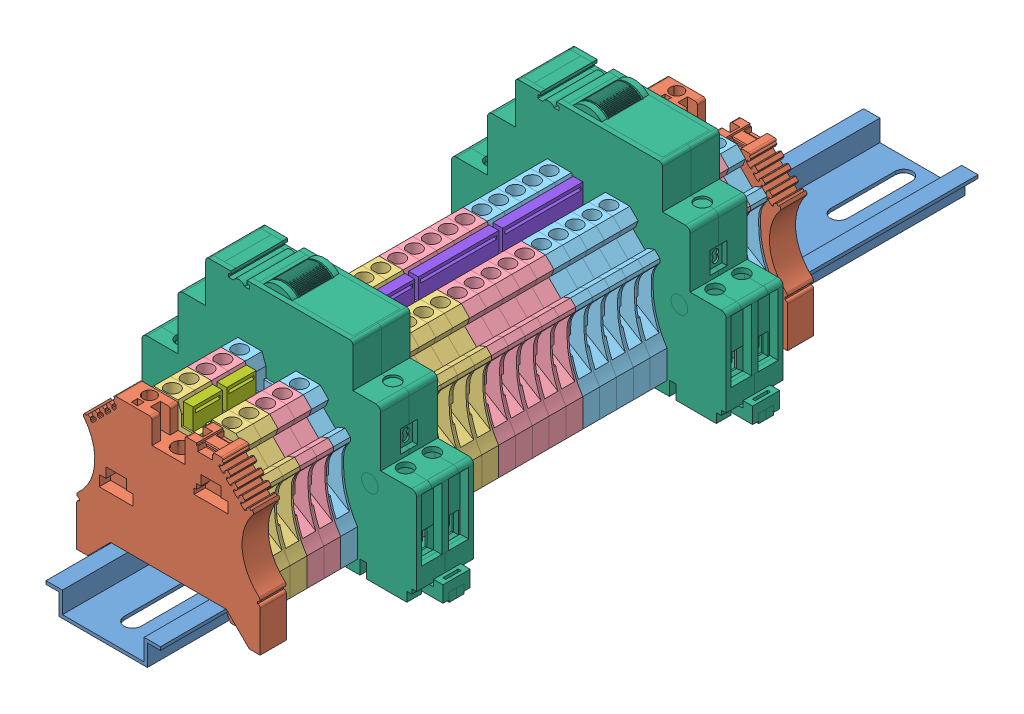
SolidWorks assembly Power Schreibtisch, configuration Standard. Lengths in mm.
Overall size (88.06 71.09 250).
33 component instances, 8 part files, 105 mates.
Components (placement in the parent):
- Hutschiene-1: Hutschiene [250] at (-17.5 -7.5 0) x (-1 0 0) z (0 0 -1) size (35 7.5 250)
- WEW_35_2-1: WEW_35_2 [Standard] at (10.49 -7 -20) x (0 0 -1) z (0 1 0) size (8 56.1 46.5)
- UT_2.5-1: UT_2.5 [Standard] at (-48.6989 10.6178 -28) x (0.992546 -0.121869 0) z (0 0 1) size (49.27 50.96 5.15)
- UT_2.5-2: UT_2.5 [Standard] at (-48.6989 10.6178 -33.15) x (0.992546 -0.121869 0) z (0 0 1) size (49.27 50.96 5.15)
- UT_2.5_BU-1: UT_2.5_BU [Standard] at (-48.6989 10.6178 -38.3) x (0.992546 -0.121869 0) z (0 0 1) size (49.27 50.96 5.15)
- UT_2.5_BU-2: UT_2.5_BU [Standard] at (-48.6989 10.6178 -43.45) x (0.992546 -0.121869 0) z (0 0 1) size (49.27 50.96 5.15)
- UT_2.5_PE-1: UT_2.5_PE [Standard] at (-48.6989 10.6178 -48.6) x (0.992546 -0.121869 0) z (0 0 1) size (49.27 50.96 5.15)
- Finder 20.22.8.230.400-1: Finder 20.22.8.230.400 [Standard] at (-33.2328 48.1119 -81.3028) x (1 0 0) z (0 -1 0) size (88.06 17.68 62.84)
- UT_2.5-3: UT_2.5 [Standard] at (-48.6989 10.6178 -71.15) x (0.992546 -0.121869 0) z (0 0 1) size (49.27 50.96 5.15)
- UT_2.5-4: UT_2.5 [Standard] at (-48.6989 10.6178 -76.3) x (0.992546 -0.121869 0) z (0 0 1) size (49.27 50.96 5.15)
- UT_2.5-5: UT_2.5 [Standard] at (-48.6989 10.6178 -81.45) x (0.992546 -0.121869 0) z (0 0 1) size (49.27 50.96 5.15)
- UT_2.5-6: UT_2.5 [Standard] at (-48.6989 10.6178 -86.6) x (0.992546 -0.121869 0) z (0 0 1) size (49.27 50.96 5.15)
- UT_2.5-7: UT_2.5 [Standard] at (-48.6989 10.6178 -91.75) x (0.992546 -0.121869 0) z (0 0 1) size (49.27 50.96 5.15)
- UT_2.5_BU-3: UT_2.5_BU [Standard] at (-48.6989 10.6178 -96.9) x (0.992546 -0.121869 0) z (0 0 1) size (49.27 50.96 5.15)
- UT_2.5_BU-4: UT_2.5_BU [Standard] at (-48.6989 10.6178 -102.05) x (0.992546 -0.121869 0) z (0 0 1) size (49.27 50.96 5.15)
- UT_2.5_BU-5: UT_2.5_BU [Standard] at (-48.6989 10.6178 -107.2) x (0.992546 -0.121869 0) z (0 0 1) size (49.27 50.96 5.15)
- UT_2.5_BU-6: UT_2.5_BU [Standard] at (-48.6989 10.6178 -112.35) x (0.992546 -0.121869 0) z (0 0 1) size (49.27 50.96 5.15)
- UT_2.5_BU-7: UT_2.5_BU [Standard] at (-48.6989 10.6178 -117.5) x (0.992546 -0.121869 0) z (0 0 1) size (49.27 50.96 5.15)
- UT_2.5_PE-2: UT_2.5_PE [Standard] at (-48.6989 10.6178 -122.65) x (0.992546 -0.121869 0) z (0 0 1) size (49.27 50.96 5.15)
- UT_2.5_PE-3: UT_2.5_PE [Standard] at (-48.6989 10.6178 -127.8) x (0.992546 -0.121869 0) z (0 0 1) size (49.27 50.96 5.15)
- UT_2.5_PE-4: UT_2.5_PE [Standard] at (-48.6989 10.6178 -132.95) x (0.992546 -0.121869 0) z (0 0 1) size (49.27 50.96 5.15)
- UT_2.5_PE-5: UT_2.5_PE [Standard] at (-48.6989 10.6178 -138.1) x (0.992546 -0.121869 0) z (0 0 1) size (49.27 50.96 5.15)
- UT_2.5_PE-6: UT_2.5_PE [Standard] at (-48.6989 10.6178 -143.25) x (0.992546 -0.121869 0) z (0 0 1) size (49.27 50.96 5.15)
- Finder 20.22.8.230.400-2: Finder 20.22.8.230.400 [Standard] at (-33.2328 48.1119 -175.9528) x (1 0 0) z (0 -1 0) size (88.06 17.68 62.84)
- UT_2.5-8: UT_2.5 [Standard] at (-48.6989 10.6178 -165.8) x (0.992546 -0.121869 0) z (0 0 1) size (49.27 50.96 5.15)
- UT_2.5_BU-8: UT_2.5_BU [Standard] at (-48.6989 10.6178 -170.95) x (0.992546 -0.121869 0) z (0 0 1) size (49.27 50.96 5.15)
- UT_2.5_PE-7: UT_2.5_PE [Standard] at (-48.6989 10.6178 -176.1) x (0.992546 -0.121869 0) z (0 0 1) size (49.27 50.96 5.15)
- WEW_35_2-2: WEW_35_2 [Standard] at (10.49 -7 -181.25) x (0 0 -1) z (0 1 0) size (8 56.1 46.5)
- FBS_2-5-1: FBS_2-5 [Standard] at (-24.1072 49.175 -86.835) size (3 22.98 9)
- FBS_2-5-3: FBS_2-5 [Standard] at (-24.1072 49.175 -97.135) size (3 22.98 9)
- FBS_5_5-1: FBS_5_5 [Standard] at (-24.1072 48.875 -130.01) size (3 22.98 24.6)
- FBS_5_5-2: FBS_5_5 [Standard] at (-24.1072 48.875 -155.735) size (3 22.98 24.6)
- FBS_5_5-3: FBS_5_5 [Standard] at (-24.1072 48.875 -181.485) size (3 22.98 24.6)
Mates (geometry in assembly coordinates):
- Deckungsgleich1: coincident aligned: plane of Hutschiene-1 through (-17.5 -7.5 0) normal (0 0 1); plane of assembly through (0 0 0) normal (0 0 1)
- Deckungsgleich2: coincident aligned: plane of Hutschiene-1 through (-35 0 -250) normal (0 1 0); plane of assembly through (0 0 0) normal (0 1 0)
- Deckungsgleich3: coincident aligned: plane of Hutschiene-1 through (0 0 -250) normal (1 0 0); plane of assembly through (0 0 0) normal (1 0 0)
- Deckungsgleich4: coincident anti-aligned: plane of Hutschiene-1 through (-35 0 -250) normal (0 1 0); plane of WEW_35_2-1 through (-35.26 0 -28) normal (0 -1 0)
- Tangential1: tangent anti-aligned: plane of Hutschiene-1 through (0 0 -250) normal (1 0 0); cylinder of WEW_35_2-1 through (2 -1.4 -24) axis (0 0 -1) radius 2
- Abstand1: distance = 20 mm aligned: plane of Hutschiene-1 through (-17.5 -7.5 0) normal (0 0 1); plane of WEW_35_2-1 through (-17.56 0 -20) normal (0 0 1)
- Deckungsgleich6: coincident anti-aligned: plane of WEW_35_2-1 through (-17.56 0 -28) normal (0 0 -1); plane of UT_2.5-1 through (0 0 -28) normal (0 0 1)
- Deckungsgleich7: coincident anti-aligned: plane of UT_2.5-1 through (0 0 -33.15) normal (0 0 -1); plane of UT_2.5-2 through (0 0 -33.15) normal (0 0 1)
- Deckungsgleich10: coincident anti-aligned: plane of Hutschiene-1 through (-35 0 -250) normal (0 1 0); plane of UT_2.5-1 through (-7.7 0 -28) normal (0 -1 0)
- Deckungsgleich11: coincident anti-aligned: plane of Hutschiene-1 through (-35 0 -250) normal (0 1 0); plane of UT_2.5-2 through (-7.7 0 -33.15) normal (0 -1 0)
- Deckungsgleich12: coincident anti-aligned: plane of Hutschiene-1 through (-35 0 -250) normal (0 1 0); plane of UT_2.5_BU-1 through (-7.7 0 -38.3) normal (0 -1 0)
- Deckungsgleich13: coincident anti-aligned: plane of Hutschiene-1 through (-35 0 -250) normal (0 1 0); plane of UT_2.5_PE-1 through (-7.7 0 -48.6) normal (0 -1 0)
- Deckungsgleich14: coincident anti-aligned: plane of Hutschiene-1 through (0 0 -250) normal (1 0 0); plane of UT_2.5-1 through (0 -1.1 -28) normal (-1 0 0)
- Deckungsgleich15: coincident anti-aligned: plane of Hutschiene-1 through (0 0 -250) normal (1 0 0); plane of UT_2.5-2 through (0 -1.1 -33.15) normal (-1 0 0)
- Deckungsgleich16: coincident anti-aligned: plane of Hutschiene-1 through (0 0 -250) normal (1 0 0); plane of UT_2.5_BU-1 through (0 -1.1 -38.3) normal (-1 0 0)
- Deckungsgleich17: coincident anti-aligned: plane of Hutschiene-1 through (0 0 -250) normal (1 0 0); plane of UT_2.5_PE-1 through (0 -1.1 -48.6) normal (-1 0 0)
- Deckungsgleich19: coincident anti-aligned: plane of Hutschiene-1 through (-35 0 -250) normal (0 1 0); plane of UT_2.5-3 through (-7.7 0 -71.15) normal (0 -1 0)
- Deckungsgleich20: coincident anti-aligned: plane of Hutschiene-1 through (0 0 -250) normal (1 0 0); plane of UT_2.5-3 through (0 -1.1 -71.15) normal (-1 0 0)
- Deckungsgleich22: coincident anti-aligned: plane of UT_2.5-1 through (-18.35 21.85 -28.475) normal (0 0 -1); plane of FBS_2-5-1 through (-18.5 39.7 -28.475) normal (0 0 1)
- Deckungsgleich23: coincident: plane of UT_2.5_BU-1 through (-16.65 21.85 -42.8) normal (0 0 1); plane of ? through (-14.8214 35.054 -42.8) normal (0 0 -1)
- Deckungsgleich24: coincident anti-aligned: plane of UT_2.5-1 through (-21.5 36.703 -28) normal (1 0 0); plane of FBS_2-5-1 through (-21.5 41.9423 -62.735) normal (-1 0 0)
- Deckungsgleich25: coincident: plane of UT_2.5-2 through (-13.5 33.5 -33.15) normal (-1 0 0); plane of ? through (-13.5 38.7586 -42.5345) normal (1 0 0)
- Deckungsgleich26: coincident: plane of UT_2.5-2 through (-12.3 40 -33.15) normal (0 1 0); plane of ? through (-13.5 40 -13.3) normal (0 1 0)
- Deckungsgleich27: coincident aligned: plane of UT_2.5-1 through (-30.1 40 -28) normal (0 1 0); plane of FBS_2-5-1 through (-18.5 40 -7.975) normal (0 1 0)
- Deckungsgleich28: coincident anti-aligned: plane of Hutschiene-1 through (-5 0 -250) normal (0 1 0); plane of Finder 20.22.8.230.400-1 through (-35.4105 0 -53.74) normal (0 -1 0)
- Deckungsgleich29: coincident anti-aligned: plane of Hutschiene-1 through (-5 0 -250) normal (0 1 0); plane of Finder 20.22.8.230.400-2 through (-35.4105 0 -148.39) normal (0 -1 0)
- Deckungsgleich30: coincident anti-aligned: plane of UT_2.5_PE-1 through (0 0 -53.75) normal (0 0 -1); plane of Finder 20.22.8.230.400-1 through (33.0017 62.5812 -53.75) normal (0 0 1)
- Deckungsgleich32: coincident anti-aligned: plane of Hutschiene-1 through (0 0 -250) normal (1 0 0); plane of Finder 20.22.8.230.400-1 through (0 -0.76 -67.785) normal (-1 0 0)
- Deckungsgleich33: coincident anti-aligned: plane of Hutschiene-1 through (0 0 -250) normal (1 0 0); plane of Finder 20.22.8.230.400-2 through (0 -0.76 -162.435) normal (-1 0 0)
- Deckungsgleich34: coincident anti-aligned: plane of UT_2.5_BU-1 through (0 0 -43.45) normal (0 0 -1); plane of UT_2.5_BU-2 through (0 0 -43.45) normal (0 0 1)
- Deckungsgleich37: coincident anti-aligned: plane of Hutschiene-1 through (-35 0 -250) normal (0 1 0); plane of UT_2.5_BU-2 through (-7.7 0 -43.45) normal (0 -1 0)
- Deckungsgleich38: coincident anti-aligned: plane of Hutschiene-1 through (-35 0 -250) normal (0 1 0); plane of UT_2.5_BU-3 through (-7.7 0 -96.9) normal (0 -1 0)
- Deckungsgleich39: coincident anti-aligned: plane of Hutschiene-1 through (0 0 -250) normal (1 0 0); plane of UT_2.5_BU-2 through (0 -1.1 -43.45) normal (-1 0 0)
- Deckungsgleich40: coincident anti-aligned: plane of Hutschiene-1 through (0 0 -250) normal (1 0 0); plane of UT_2.5_BU-3 through (0 -1.1 -96.9) normal (-1 0 0)
- Deckungsgleich41: coincident anti-aligned: plane of UT_2.5_BU-1 through (-21.5 36.703 -38.3) normal (1 0 0); plane of FBS_2-5-3 through (-21.5 41.9423 -73.035) normal (-1 0 0)
- Deckungsgleich42: coincident anti-aligned: plane of UT_2.5_BU-3 through (-13.5 33.5 -53.75) normal (-1 0 0); plane of ? through (-13.5 38.7586 -57.9845) normal (1 0 0)
- Deckungsgleich43: coincident anti-aligned: plane of UT_2.5_BU-1 through (-18.35 21.85 -38.775) normal (0 0 -1); plane of FBS_2-5-3 through (-18.5 39.7 -38.775) normal (0 0 1)
- Deckungsgleich44: coincident anti-aligned: plane of UT_2.5_BU-3 through (-16.65 21.85 -58.25) normal (0 0 1); plane of ? through (-14.8214 35.054 -58.25) normal (0 0 -1)
- Deckungsgleich45: coincident aligned: plane of UT_2.5_BU-1 through (-30.1 40 -38.3) normal (0 1 0); plane of FBS_2-5-3 through (-18.5 40 -18.275) normal (0 1 0)
- Deckungsgleich46: coincident aligned: plane of UT_2.5_BU-3 through (-12.3 40 -53.75) normal (0 1 0); plane of ? through (-13.5 40 -28.75) normal (0 1 0)
- Deckungsgleich47: coincident anti-aligned: plane of UT_2.5-2 through (0 0 -38.3) normal (0 0 -1); plane of UT_2.5_BU-1 through (0 0 -38.3) normal (0 0 1)
- Deckungsgleich48: coincident anti-aligned: plane of UT_2.5_BU-2 through (0 0 -48.6) normal (0 0 -1); plane of UT_2.5_PE-1 through (0 0 -48.6) normal (0 0 1)
- Deckungsgleich49: coincident anti-aligned: plane of UT_2.5-3 through (0 0 -71.15) normal (0 0 1); plane of Finder 20.22.8.230.400-1 through (33.0013 -10.3807 -71.15) normal (0 0 -1)
- Deckungsgleich50: coincident anti-aligned: plane of UT_2.5-3 through (0 0 -76.3) normal (0 0 -1); plane of UT_2.5-4 through (0 0 -76.3) normal (0 0 1)
- Deckungsgleich51: coincident anti-aligned: plane of UT_2.5-4 through (0 0 -81.45) normal (0 0 -1); plane of UT_2.5-5 through (0 0 -81.45) normal (0 0 1)
- Deckungsgleich52: coincident anti-aligned: plane of UT_2.5-5 through (0 0 -86.6) normal (0 0 -1); plane of UT_2.5-6 through (0 0 -86.6) normal (0 0 1)
- Deckungsgleich53: coincident anti-aligned: plane of UT_2.5-6 through (0 0 -91.75) normal (0 0 -1); plane of UT_2.5-7 through (0 0 -91.75) normal (0 0 1)
- Deckungsgleich54: coincident anti-aligned: plane of Hutschiene-1 through (-35 0 -250) normal (0 1 0); plane of UT_2.5-4 through (-7.7 0 -76.3) normal (0 -1 0)
- Deckungsgleich55: coincident anti-aligned: plane of Hutschiene-1 through (-35 0 -250) normal (0 1 0); plane of UT_2.5-5 through (-7.7 0 -81.45) normal (0 -1 0)
- Deckungsgleich56: coincident anti-aligned: plane of Hutschiene-1 through (-35 0 -250) normal (0 1 0); plane of UT_2.5-6 through (-7.7 0 -86.6) normal (0 -1 0)
- Deckungsgleich57: coincident anti-aligned: plane of Hutschiene-1 through (-35 0 -250) normal (0 1 0); plane of UT_2.5-7 through (-7.7 0 -91.75) normal (0 -1 0)
- Deckungsgleich58: coincident anti-aligned: plane of Hutschiene-1 through (0 0 -250) normal (1 0 0); plane of UT_2.5-4 through (0 -1.1 -76.3) normal (-1 0 0)
- Deckungsgleich59: coincident anti-aligned: plane of Hutschiene-1 through (0 0 -250) normal (1 0 0); plane of UT_2.5-5 through (0 -1.1 -81.45) normal (-1 0 0)
- Deckungsgleich60: coincident anti-aligned: plane of Hutschiene-1 through (0 0 -250) normal (1 0 0); plane of UT_2.5-6 through (0 -1.1 -86.6) normal (-1 0 0)
- Deckungsgleich61: coincident anti-aligned: plane of Hutschiene-1 through (0 0 -250) normal (1 0 0); plane of UT_2.5-7 through (0 -1.1 -91.75) normal (-1 0 0)
- Deckungsgleich62: coincident anti-aligned: plane of UT_2.5_BU-3 through (0 0 -102.05) normal (0 0 -1); plane of UT_2.5_BU-4 through (0 0 -102.05) normal (0 0 1)
- Deckungsgleich63: coincident anti-aligned: plane of UT_2.5_BU-4 through (0 0 -107.2) normal (0 0 -1); plane of UT_2.5_BU-5 through (0 0 -107.2) normal (0 0 1)
- Deckungsgleich64: coincident anti-aligned: plane of UT_2.5_BU-5 through (0 0 -112.35) normal (0 0 -1); plane of UT_2.5_BU-6 through (0 0 -112.35) normal (0 0 1)
- Deckungsgleich65: coincident anti-aligned: plane of UT_2.5_BU-6 through (0 0 -117.5) normal (0 0 -1); plane of UT_2.5_BU-7 through (0 0 -117.5) normal (0 0 1)
- Deckungsgleich66: coincident anti-aligned: plane of UT_2.5_BU-7 through (0 0 -122.65) normal (0 0 -1); plane of UT_2.5_PE-2 through (0 0 -122.65) normal (0 0 1)
- Deckungsgleich67: coincident anti-aligned: plane of UT_2.5_PE-2 through (0 0 -127.8) normal (0 0 -1); plane of UT_2.5_PE-3 through (0 0 -127.8) normal (0 0 1)
- Deckungsgleich68: coincident anti-aligned: plane of UT_2.5_PE-3 through (0 0 -132.95) normal (0 0 -1); plane of UT_2.5_PE-4 through (0 0 -132.95) normal (0 0 1)
- Deckungsgleich69: coincident anti-aligned: plane of UT_2.5_PE-4 through (0 0 -138.1) normal (0 0 -1); plane of UT_2.5_PE-5 through (0 0 -138.1) normal (0 0 1)
- Deckungsgleich70: coincident anti-aligned: plane of UT_2.5_PE-5 through (0 0 -143.25) normal (0 0 -1); plane of UT_2.5_PE-6 through (0 0 -143.25) normal (0 0 1)
- Deckungsgleich71: coincident anti-aligned: plane of UT_2.5_PE-6 through (0 0 -148.4) normal (0 0 -1); plane of Finder 20.22.8.230.400-2 through (33.0017 62.5812 -148.4) normal (0 0 1)
- Deckungsgleich72: coincident anti-aligned: plane of Finder 20.22.8.230.400-2 through (33.0013 -10.3807 -165.8) normal (0 0 -1); plane of UT_2.5-8 through (0 0 -165.8) normal (0 0 1)
- Deckungsgleich73: coincident anti-aligned: plane of UT_2.5-8 through (0 0 -170.95) normal (0 0 -1); plane of UT_2.5_BU-8 through (0 0 -170.95) normal (0 0 1)
- Deckungsgleich74: coincident anti-aligned: plane of UT_2.5_BU-8 through (0 0 -176.1) normal (0 0 -1); plane of UT_2.5_PE-7 through (0 0 -176.1) normal (0 0 1)
- Deckungsgleich75: coincident anti-aligned: plane of UT_2.5_PE-7 through (0 0 -181.25) normal (0 0 -1); plane of WEW_35_2-2 through (-17.56 0 -181.25) normal (0 0 1)
- Deckungsgleich76: coincident anti-aligned: plane of UT_2.5-7 through (0 0 -96.9) normal (0 0 -1); plane of UT_2.5_BU-3 through (0 0 -96.9) normal (0 0 1)
- Deckungsgleich77: coincident anti-aligned: plane of Hutschiene-1 through (-35 0 -250) normal (0 1 0); plane of UT_2.5_BU-4 through (-7.7 0 -102.05) normal (0 -1 0)
- Deckungsgleich78: coincident anti-aligned: plane of Hutschiene-1 through (-35 0 -250) normal (0 1 0); plane of UT_2.5_BU-5 through (-7.7 0 -107.2) normal (0 -1 0)
- Deckungsgleich79: coincident anti-aligned: plane of Hutschiene-1 through (-35 0 -250) normal (0 1 0); plane of UT_2.5_BU-6 through (-7.7 0 -112.35) normal (0 -1 0)
- Deckungsgleich80: coincident anti-aligned: plane of Hutschiene-1 through (-35 0 -250) normal (0 1 0); plane of UT_2.5_BU-7 through (-7.7 0 -117.5) normal (0 -1 0)
- Deckungsgleich81: coincident anti-aligned: plane of Hutschiene-1 through (-35 0 -250) normal (0 1 0); plane of UT_2.5_PE-2 through (-7.7 0 -122.65) normal (0 -1 0)
- Deckungsgleich82: coincident anti-aligned: plane of Hutschiene-1 through (-35 0 -250) normal (0 1 0); plane of UT_2.5_PE-3 through (-7.7 0 -127.8) normal (0 -1 0)
- Deckungsgleich83: coincident anti-aligned: plane of Hutschiene-1 through (-35 0 -250) normal (0 1 0); plane of UT_2.5_PE-5 through (-7.7 0 -138.1) normal (0 -1 0)
- Deckungsgleich84: coincident anti-aligned: plane of Hutschiene-1 through (-35 0 -250) normal (0 1 0); plane of UT_2.5_PE-4 through (-7.7 0 -132.95) normal (0 -1 0)
- Deckungsgleich85: coincident anti-aligned: plane of Hutschiene-1 through (-35 0 -250) normal (0 1 0); plane of UT_2.5_PE-6 through (-7.7 0 -143.25) normal (0 -1 0)
- Deckungsgleich86: coincident anti-aligned: plane of Hutschiene-1 through (-35 0 -250) normal (0 1 0); plane of UT_2.5-8 through (-7.7 0 -165.8) normal (0 -1 0)
- Deckungsgleich87: coincident anti-aligned: plane of Hutschiene-1 through (-35 0 -250) normal (0 1 0); plane of UT_2.5_BU-8 through (-7.7 0 -170.95) normal (0 -1 0)
- Deckungsgleich88: coincident anti-aligned: plane of Hutschiene-1 through (-35 0 -250) normal (0 1 0); plane of UT_2.5_PE-7 through (-7.7 0 -176.1) normal (0 -1 0)
- Deckungsgleich89: coincident anti-aligned: plane of Hutschiene-1 through (-35 0 -250) normal (0 1 0); plane of WEW_35_2-2 through (-35.26 0 -189.25) normal (0 -1 0)
- Deckungsgleich90: coincident anti-aligned: plane of Hutschiene-1 through (0 0 -250) normal (1 0 0); plane of UT_2.5_BU-4 through (0 -1.1 -102.05) normal (-1 0 0)
- Deckungsgleich91: coincident anti-aligned: plane of Hutschiene-1 through (0 0 -250) normal (1 0 0); plane of UT_2.5_BU-5 through (0 -1.1 -107.2) normal (-1 0 0)
- Deckungsgleich92: coincident anti-aligned: plane of Hutschiene-1 through (0 0 -250) normal (1 0 0); plane of UT_2.5_BU-6 through (0 -1.1 -112.35) normal (-1 0 0)
- Deckungsgleich93: coincident anti-aligned: plane of Hutschiene-1 through (0 0 -250) normal (1 0 0); plane of UT_2.5_BU-7 through (0 -1.1 -117.5) normal (-1 0 0)
- Deckungsgleich94: coincident anti-aligned: plane of Hutschiene-1 through (0 0 -250) normal (1 0 0); plane of UT_2.5_PE-2 through (0 -1.1 -122.65) normal (-1 0 0)
- Deckungsgleich95: coincident anti-aligned: plane of Hutschiene-1 through (0 0 -250) normal (1 0 0); plane of UT_2.5_PE-3 through (0 -1.1 -127.8) normal (-1 0 0)
- Deckungsgleich96: coincident anti-aligned: plane of Hutschiene-1 through (0 0 -250) normal (1 0 0); plane of UT_2.5_PE-4 through (0 -1.1 -132.95) normal (-1 0 0)
- Deckungsgleich97: coincident anti-aligned: plane of Hutschiene-1 through (0 0 -250) normal (1 0 0); plane of UT_2.5_PE-5 through (0 -1.1 -138.1) normal (-1 0 0)
- Deckungsgleich98: coincident anti-aligned: plane of Hutschiene-1 through (0 0 -250) normal (1 0 0); plane of UT_2.5_PE-6 through (0 -1.1 -143.25) normal (-1 0 0)
- Deckungsgleich99: coincident anti-aligned: plane of Hutschiene-1 through (0 0 -250) normal (1 0 0); plane of UT_2.5-8 through (0 -1.1 -165.8) normal (-1 0 0)
- Deckungsgleich100: coincident anti-aligned: plane of Hutschiene-1 through (0 0 -250) normal (1 0 0); plane of UT_2.5_BU-8 through (0 -1.1 -170.95) normal (-1 0 0)
- Deckungsgleich101: coincident anti-aligned: plane of Hutschiene-1 through (0 0 -250) normal (1 0 0); plane of UT_2.5_PE-7 through (0 -1.1 -176.1) normal (-1 0 0)
- Tangential2: tangent anti-aligned: plane of Hutschiene-1 through (0 0 -250) normal (1 0 0); cylinder of WEW_35_2-2 through (2 -1.4 -185.25) axis (0 0 -1) radius 2
- Deckungsgleich102: coincident anti-aligned: plane of UT_2.5-3 through (-21.5 36.703 -71.15) normal (1 0 0); plane of FBS_5_5-1 through (-21.5 38.7586 -85.5845) normal (-1 0 0)
- Deckungsgleich103: coincident anti-aligned: plane of UT_2.5_BU-4 through (-21.5 36.703 -102.05) normal (1 0 0); plane of FBS_5_5-2 through (-21.5 38.7586 -111.3095) normal (-1 0 0)
- Deckungsgleich104: coincident anti-aligned: plane of UT_2.5_PE-3 through (-21.5 36.703 -127.8) normal (1 0 0); plane of FBS_5_5-3 through (-21.5 38.7586 -137.0595) normal (-1 0 0)
- Deckungsgleich105: coincident anti-aligned: plane of UT_2.5-7 through (-21.5 21.85 -96.25) normal (0 0 1); plane of FBS_5_5-1 through (-18.5 39.7 -96.25) normal (0 0 -1)
- Deckungsgleich106: coincident anti-aligned: plane of UT_2.5_BU-3 through (-18.35 21.85 -97.375) normal (0 0 -1); plane of FBS_5_5-2 through (-18.5 39.7 -97.375) normal (0 0 1)
- Deckungsgleich107: coincident anti-aligned: plane of UT_2.5_PE-2 through (-18.35 21.85 -123.125) normal (0 0 -1); plane of FBS_5_5-3 through (-18.5 39.7 -123.125) normal (0 0 1)
- Deckungsgleich108: coincident aligned: plane of UT_2.5-7 through (-30.1 40 -91.75) normal (0 1 0); plane of FBS_5_5-1 through (-18.5 40 -82.05) normal (0 1 0)
- Deckungsgleich109: coincident aligned: plane of UT_2.5_BU-3 through (-30.1 40 -96.9) normal (0 1 0); plane of FBS_5_5-2 through (-18.5 40 -107.775) normal (0 1 0)
- Deckungsgleich110: coincident aligned: plane of UT_2.5_PE-2 through (-30.1 40 -122.65) normal (0 1 0); plane of FBS_5_5-3 through (-18.5 40 -133.525) normal (0 1 0)
